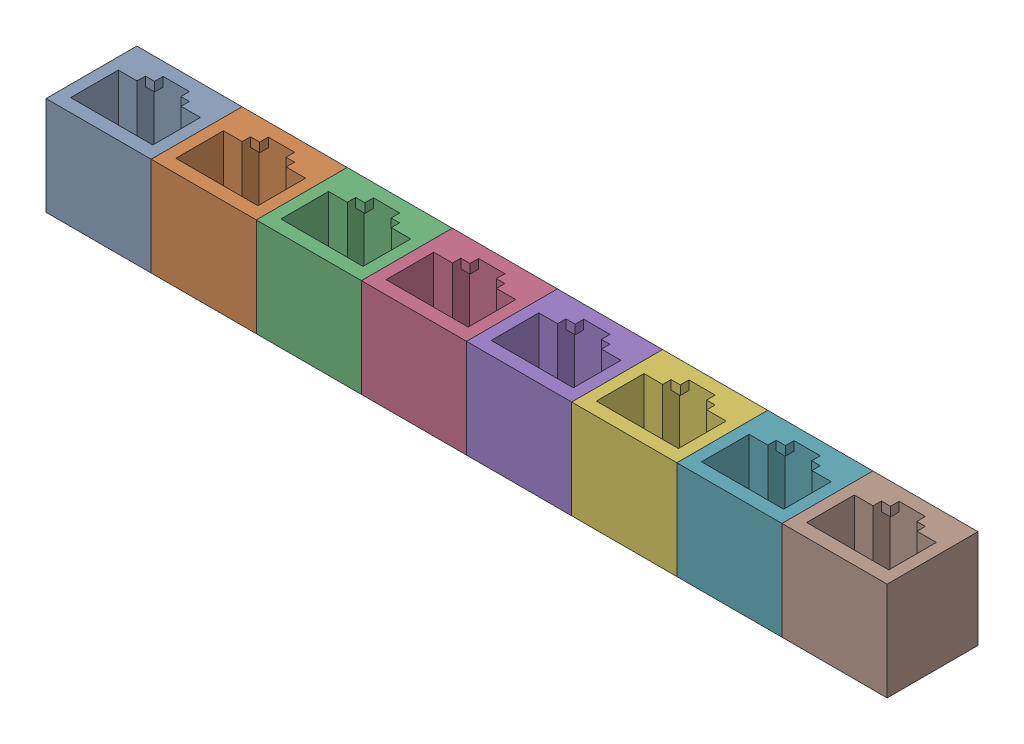
SolidWorks assembly 16-port block, configuration Default. Lengths in mm.
Overall size (128 15 13.83).
8 component instances, 1 part files, 21 mates.
Components (placement in the parent):
- RJ45 dummy jack trimmed-1: RJ45 dummy jack trimmed [Default] at (-39.7791 5.8279 33.2634) size (16 15 13.83)
- RJ45 dummy jack trimmed-2: RJ45 dummy jack trimmed [Default] at (-23.7791 5.8279 33.2634) size (16 15 13.83)
- RJ45 dummy jack trimmed-3: RJ45 dummy jack trimmed [Default] at (-7.7791 5.8279 33.2634) size (16 15 13.83)
- RJ45 dummy jack trimmed-4: RJ45 dummy jack trimmed [Default] at (8.2209 5.8279 33.2634) size (16 15 13.83)
- RJ45 dummy jack trimmed-5: RJ45 dummy jack trimmed [Default] at (24.2209 5.8279 33.2634) size (16 15 13.83)
- RJ45 dummy jack trimmed-6: RJ45 dummy jack trimmed [Default] at (40.2209 5.8279 33.2634) size (16 15 13.83)
- RJ45 dummy jack trimmed-7: RJ45 dummy jack trimmed [Default] at (56.2209 5.8279 33.2634) size (16 15 13.83)
- RJ45 dummy jack trimmed-8: RJ45 dummy jack trimmed [Default] at (72.2209 5.8279 33.2634) size (16 15 13.83)
Mates (geometry in assembly coordinates):
- Coincident1: coincident anti-aligned: plane of RJ45 dummy jack trimmed-7 through (70.4709 30.8279 21.4334) normal (1 0 0); plane of RJ45 dummy jack trimmed-8 through (70.4709 30.8279 21.4334) normal (-1 0 0)
- Coincident2: coincident: point of RJ45 dummy jack trimmed-8; unknown of RJ45 dummy jack trimmed-7
- Coincident3: coincident: unknown of RJ45 dummy jack trimmed-7; unknown of RJ45 dummy jack trimmed-8
- Coincident5: coincident anti-aligned: plane of RJ45 dummy jack trimmed-6 through (54.4709 30.8279 21.4334) normal (1 0 0); plane of RJ45 dummy jack trimmed-7 through (54.4709 30.8279 21.4334) normal (-1 0 0)
- Coincident6: coincident anti-aligned: plane of RJ45 dummy jack trimmed-5 through (38.4709 30.8279 21.4334) normal (1 0 0); plane of RJ45 dummy jack trimmed-6 through (38.4709 30.8279 21.4334) normal (-1 0 0)
- Coincident7: coincident anti-aligned: plane of RJ45 dummy jack trimmed-4 through (22.4709 30.8279 21.4334) normal (1 0 0); plane of RJ45 dummy jack trimmed-5 through (22.4709 30.8279 21.4334) normal (-1 0 0)
- Coincident8: coincident anti-aligned: plane of RJ45 dummy jack trimmed-3 through (6.4709 30.8279 21.4334) normal (1 0 0); plane of RJ45 dummy jack trimmed-4 through (6.4709 30.8279 21.4334) normal (-1 0 0)
- Coincident9: coincident anti-aligned: plane of RJ45 dummy jack trimmed-2 through (-9.5291 30.8279 21.4334) normal (1 0 0); plane of RJ45 dummy jack trimmed-3 through (-9.5291 30.8279 21.4334) normal (-1 0 0)
- Coincident10: coincident anti-aligned: plane of RJ45 dummy jack trimmed-1 through (-25.5291 30.8279 21.4334) normal (1 0 0); plane of RJ45 dummy jack trimmed-2 through (-25.5291 30.8279 21.4334) normal (-1 0 0)
- Coincident11: coincident: unknown of RJ45 dummy jack trimmed-6; unknown of RJ45 dummy jack trimmed-7
- Coincident12: coincident: unknown of RJ45 dummy jack trimmed-6; unknown of RJ45 dummy jack trimmed-7
- Coincident13: coincident: unknown of RJ45 dummy jack trimmed-5; unknown of RJ45 dummy jack trimmed-6
- Coincident14: coincident: unknown of RJ45 dummy jack trimmed-5; unknown of RJ45 dummy jack trimmed-6
- Coincident15: coincident: unknown of RJ45 dummy jack trimmed-4; unknown of RJ45 dummy jack trimmed-5
- Coincident16: coincident: unknown of RJ45 dummy jack trimmed-4; unknown of RJ45 dummy jack trimmed-5
- Coincident17: coincident: unknown of RJ45 dummy jack trimmed-3; unknown of RJ45 dummy jack trimmed-4
- Coincident18: coincident: unknown of RJ45 dummy jack trimmed-3; unknown of RJ45 dummy jack trimmed-4
- Coincident19: coincident: unknown of RJ45 dummy jack trimmed-2; unknown of RJ45 dummy jack trimmed-3
- Coincident20: coincident: unknown of RJ45 dummy jack trimmed-2; unknown of RJ45 dummy jack trimmed-3
- Coincident21: coincident: unknown of RJ45 dummy jack trimmed-1; unknown of RJ45 dummy jack trimmed-2
- Coincident22: coincident: unknown of RJ45 dummy jack trimmed-1; unknown of RJ45 dummy jack trimmed-2
